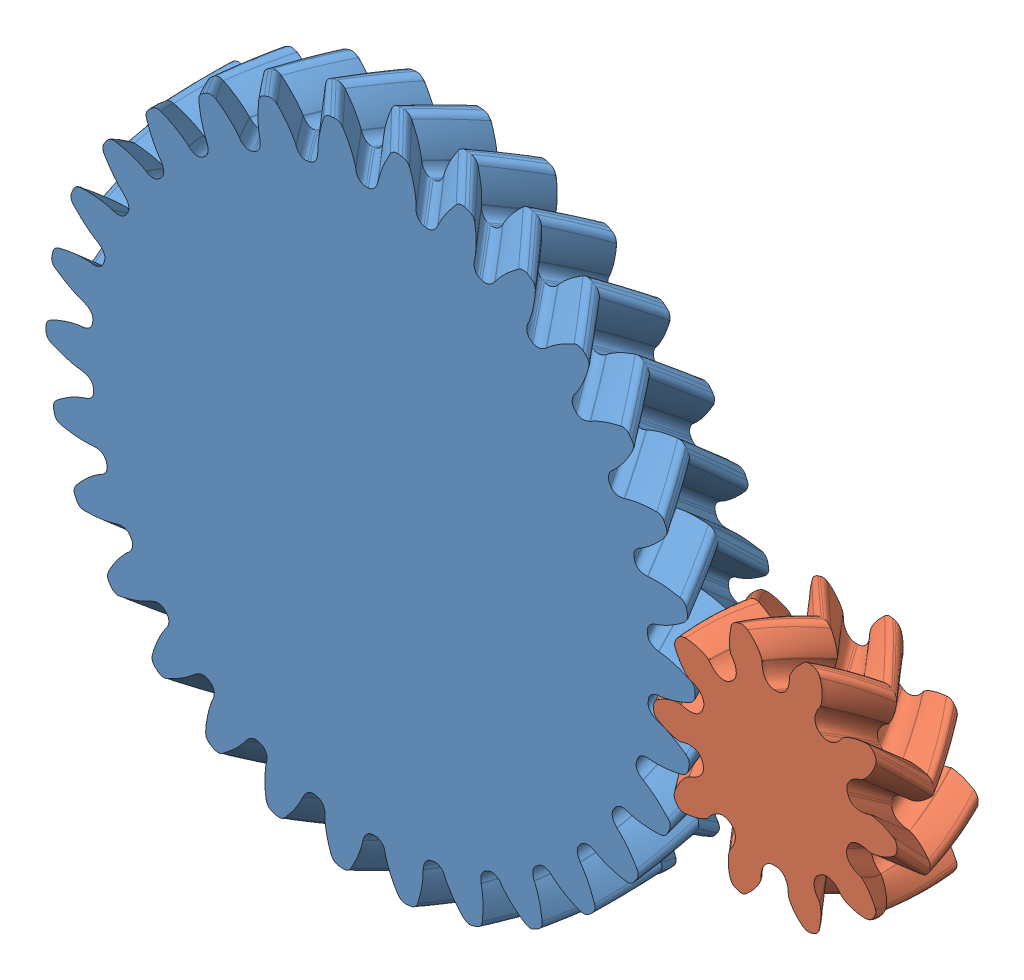
SolidWorks assembly Herringbone Gears Assembly, configuration Default. Lengths in mm.
Overall size (88.18 77.17 7.96).
2 component instances, 2 part files, 5 mates.
Components (placement in the parent):
- Big Herringbone Gear-1: Big Herringbone Gear [30 Tooth] at (0 0 -7) x (-0.859903 -0.510457 0) z (0 0 1) size (56.14 56.41 7.96)
- Small Herringbone Gear-1: Small Herringbone Gear [10 Tooth] at (34.9117 -2.485 -7) x (-0.585325 0.810799 0) z (0 0 1) size (21.08 21.12 7.86)
Mates (geometry in assembly coordinates):
- Coincident4: coincident: point of Big Herringbone Gear-1
- Parallel1: parallel anti-aligned: plane of Big Herringbone Gear-1 through (14.7421 -22.7726 -7) normal (0 0 -1)
- Coincident6: coincident aligned: plane of Small Herringbone Gear-1 through (27.5555 -8.9792 0) normal (0 0 1)
- Tangent1: tangent: circle of Big Herringbone Gear-1; circle of Small Herringbone Gear-1
- GearMate1: gear = 17.5 : 52.5 mm: circle of Big Herringbone Gear-1; circle of Small Herringbone Gear-1
